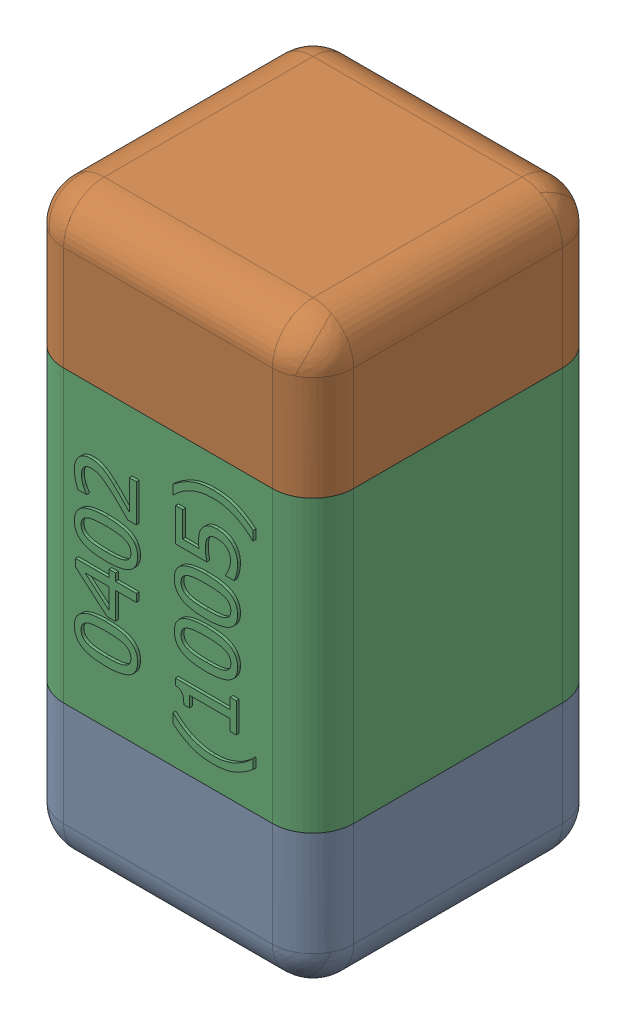
SolidWorks assembly C45, configuration Standard. Lengths in mm.
Overall size (0.51 1.01 0.51).
4 component instances, 3 part files, 0 mates.
Components (placement in the parent):
- C45-subassembly-1-1: C45-subassembly-1 [Standard] at (-0.6 -17.8999 0) x (0 1 0) z (0 0 1) size (1.01 0.51 0.51)
  - User Library-0402_Cap-1: User Library-0402_Cap [Standard] at origin size (0.26 0.51 0.51)
  - User Library-0402_Cap-1-1: User Library-0402_Cap-1 [Standard] at origin size (0.26 0.5 0.51)
  - User Library-0402_Cap-2-1: User Library-0402_Cap-2 [Standard] at origin size (0.5 0.5 0.51)
